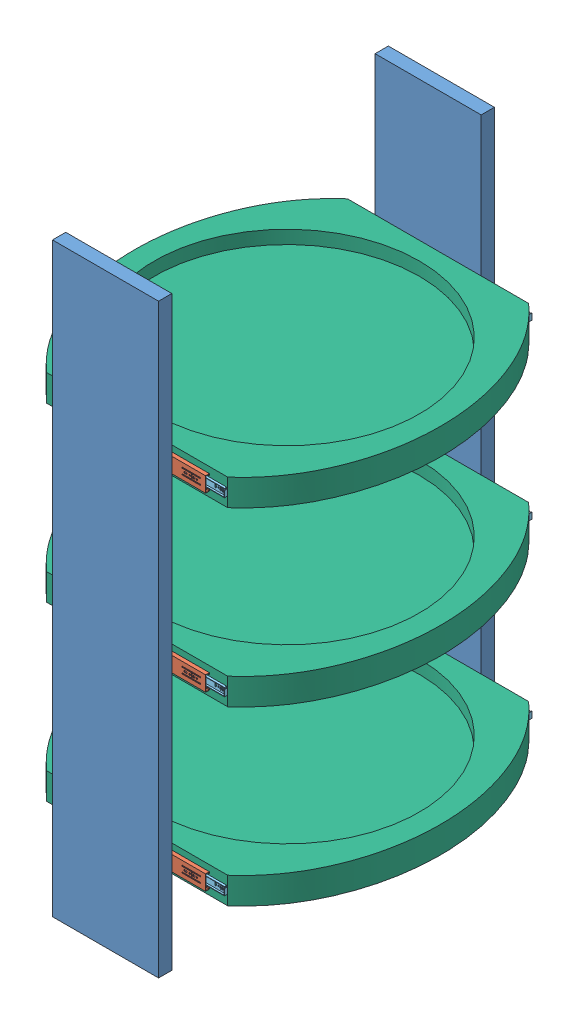
SolidWorks assembly second_prototype, configuration Default. Lengths in mm.
Overall size (230.71 442 253.27).
35 component instances, 6 part files, 39 mates.
Components (placement in the parent):
- slider_holder-1: slider_holder [Default] at (0 0 117.4091) size (80 442 10)
- slider_holder-2: slider_holder [Default] at (0 0 -125.863) size (80 442 10)
- 2831110-21: 2831110 [Default] at (-216.0204 -151 -117.7235) x (0 0 1) z (1 0 0) size (3.17 11.42 125.91) (flexible)
  - 3832-0045TR Outer Member-1: 3832-0045TR Outer Member [Default] at origin size (2.85 11.42 112.5)
  - 3832TR Touch Release-1: 3832TR Touch Release [Default] at (-5.6264 0.6754 178.2964) x (0 -1 0) z (1 0 0) size (10.79 18 2.25)
  - 3832-0045TR Inter-1: 3832-0045TR Inter [Default] at (-0.6578 0.0001 415.8579) x (0 1 0) z (0 0 -1) size (8.7 2.43 90.5)
  - 3832-0045TR Inner Member-1: 3832-0045TR Inner Member [Default] at (-1.9688 0 36.7668) x (0 -1 0) z (0 0 1) size (6.1 2.47 102)
- 2831110-22: 2831110 [Default] at (-216.0204 -151 109.2696) x (0 0 -1) z (1 0 0) size (3.17 11.42 125.91) (flexible)
  - 3832-0045TR Outer Member-1: 3832-0045TR Outer Member [Default] at origin size (2.85 11.42 112.5)
  - 3832TR Touch Release-1: 3832TR Touch Release [Default] at (-5.6264 0.6754 178.2964) x (0 -1 0) z (1 0 0) size (10.79 18 2.25)
  - 3832-0045TR Inter-1: 3832-0045TR Inter [Default] at (-0.6578 0.0001 415.8579) x (0 1 0) z (0 0 -1) size (8.7 2.43 90.5)
  - 3832-0045TR Inner Member-1: 3832-0045TR Inner Member [Default] at (-1.9688 0 36.7668) x (0 -1 0) z (0 0 1) size (6.1 2.47 102)
- dispenserHolder-12: dispenserHolder [Default] at (10.059 -151 -4.2269) x (-1 0 0) z (0 0 -1) size (230.71 20.02 226.94)
- 2831110-27: 2831110 [Default] at (-216.0204 -21 -117.7235) x (0 0 1) z (1 0 0) size (3.17 11.42 125.91) (flexible)
  - 3832-0045TR Outer Member-1: 3832-0045TR Outer Member [Default] at origin size (2.85 11.42 112.5)
  - 3832TR Touch Release-1: 3832TR Touch Release [Default] at (-5.6264 0.6754 178.2964) x (0 -1 0) z (1 0 0) size (10.79 18 2.25)
  - 3832-0045TR Inter-1: 3832-0045TR Inter [Default] at (-0.6578 0.0001 415.8579) x (0 1 0) z (0 0 -1) size (8.7 2.43 90.5)
  - 3832-0045TR Inner Member-1: 3832-0045TR Inner Member [Default] at (-1.9688 0 36.7668) x (0 -1 0) z (0 0 1) size (6.1 2.47 102)
- 2831110-28: 2831110 [Default] at (-216.0204 -21 109.2696) x (0 0 -1) z (1 0 0) size (3.17 11.42 125.91) (flexible)
  - 3832-0045TR Outer Member-1: 3832-0045TR Outer Member [Default] at origin size (2.85 11.42 112.5)
  - 3832TR Touch Release-1: 3832TR Touch Release [Default] at (-5.6264 0.6754 178.2964) x (0 -1 0) z (1 0 0) size (10.79 18 2.25)
  - 3832-0045TR Inter-1: 3832-0045TR Inter [Default] at (-0.6578 0.0001 415.8579) x (0 1 0) z (0 0 -1) size (8.7 2.43 90.5)
  - 3832-0045TR Inner Member-1: 3832-0045TR Inner Member [Default] at (-1.9688 0 36.7668) x (0 -1 0) z (0 0 1) size (6.1 2.47 102)
- dispenserHolder-15: dispenserHolder [Default] at (10.059 -21 -4.2269) x (-1 0 0) z (0 0 -1) size (230.71 20.02 226.94)
- 2831110-29: 2831110 [Default] at (-216.0204 109 -117.7235) x (0 0 1) z (1 0 0) size (3.17 11.42 125.91) (flexible)
  - 3832-0045TR Outer Member-1: 3832-0045TR Outer Member [Default] at origin size (2.85 11.42 112.5)
  - 3832TR Touch Release-1: 3832TR Touch Release [Default] at (-5.6264 0.6754 178.2964) x (0 -1 0) z (1 0 0) size (10.79 18 2.25)
  - 3832-0045TR Inter-1: 3832-0045TR Inter [Default] at (-0.6578 0.0001 415.8579) x (0 1 0) z (0 0 -1) size (8.7 2.43 90.5)
  - 3832-0045TR Inner Member-1: 3832-0045TR Inner Member [Default] at (-1.9688 0 36.7668) x (0 -1 0) z (0 0 1) size (6.1 2.47 102)
- 2831110-30: 2831110 [Default] at (-216.0204 109 109.2696) x (0 0 -1) z (1 0 0) size (3.17 11.42 125.91) (flexible)
  - 3832-0045TR Outer Member-1: 3832-0045TR Outer Member [Default] at origin size (2.85 11.42 112.5)
  - 3832TR Touch Release-1: 3832TR Touch Release [Default] at (-5.6264 0.6754 178.2964) x (0 -1 0) z (1 0 0) size (10.79 18 2.25)
  - 3832-0045TR Inter-1: 3832-0045TR Inter [Default] at (-0.6578 0.0001 415.8579) x (0 1 0) z (0 0 -1) size (8.7 2.43 90.5)
  - 3832-0045TR Inner Member-1: 3832-0045TR Inner Member [Default] at (-1.9688 0 36.7668) x (0 -1 0) z (0 0 1) size (6.1 2.47 102)
- dispenserHolder-16: dispenserHolder [Default] at (10.059 109 -4.2269) x (-1 0 0) z (0 0 -1) size (230.71 20.02 226.94)
Mates (geometry in assembly coordinates):
- Coincident31: coincident aligned: plane of slider_holder-1 through (40 221 122.4091) normal (1 0 0); plane of slider_holder-2 through (40 221 -120.863) normal (1 0 0)
- Coincident32: coincident aligned: plane of slider_holder-1 through (-40 221 122.4091) normal (0 1 0); plane of slider_holder-2 through (-40 221 -120.863) normal (0 1 0)
- Coincident33: coincident anti-aligned: plane of 2831110-21/3832-0045TR Inner Member-1 through (-23.1493 -151 -117.688) normal (0 0 1); plane of dispenserHolder-12 through (125.9996 -161.01 -117.688) normal (0 0 -1)
- Coincident34: coincident anti-aligned: plane of slider_holder-2 through (0 0 -120.863) normal (0 0 1); plane of 2831110-21/3832-0045TR Outer Member-1 through (-47.0625 -151 -120.863) normal (0 0 -1)
- Coincident35: coincident anti-aligned: plane of slider_holder-1 through (0 0 112.4091) normal (0 0 -1); plane of 2831110-22/3832-0045TR Outer Member-1 through (-47.0625 -151 112.4091) normal (0 0 1)
- Coincident36: coincident anti-aligned: plane of 2831110-22/3832-0045TR Inner Member-1 through (-23.1493 -151 109.2341) normal (0 0 -1); plane of dispenserHolder-12 through (125.9996 -161.01 109.2341) normal (0 0 1)
- Coincident37: coincident aligned: plane of 2831110-21/3832-0045TR Inner Member-1 through (78.8507 -147.95 -117.688) normal (1 0 0); plane of 2831110-22/3832-0045TR Inner Member-1 through (78.8507 -154.05 109.2341) normal (1 0 0)
- Width7: width anti-aligned: plane of 2831110-22/3832-0045TR Outer Member-1 through (-47.0625 -145.2875 112.4091) normal (0 1 0); plane of dispenserHolder-12 through (65.4375 -156.7125 112.4091) normal (0 -1 0); plane of 2831110-22/3832-0045TR Outer Member-1 through (10.059 -161 -4.2269) normal (0 -1 0); plane of dispenserHolder-12 through (10.059 -141 -4.2269) normal (0 1 0)
- Width8: width aligned: plane of 2831110-21/3832-0045TR Outer Member-1 through (65.4375 -145.2875 -120.863) normal (0 1 0); plane of dispenserHolder-12 through (-47.0625 -156.7125 -120.863) normal (0 -1 0); plane of 2831110-21/3832-0045TR Outer Member-1 through (10.059 -141 -4.2269) normal (0 1 0); plane of dispenserHolder-12 through (10.059 -161 -4.2269) normal (0 -1 0)
- Coincident39: coincident anti-aligned: plane of 2831110-27/3832-0045TR Inner Member-1 through (-23.1493 -21 -117.688) normal (0 0 1); plane of dispenserHolder-15 through (125.9996 -31.01 -117.688) normal (0 0 -1)
- Width9: width aligned: plane of 2831110-27/3832-0045TR Outer Member-1 through (65.4375 -15.2875 -120.863) normal (0 1 0); plane of dispenserHolder-15 through (-47.0625 -26.7125 -120.863) normal (0 -1 0); plane of 2831110-27/3832-0045TR Outer Member-1 through (10.059 -11 -4.2269) normal (0 1 0); plane of dispenserHolder-15 through (10.059 -31 -4.2269) normal (0 -1 0)
- Width10: width anti-aligned: plane of 2831110-28/3832-0045TR Outer Member-1 through (-47.0625 -15.2875 112.4091) normal (0 1 0); plane of dispenserHolder-15 through (65.4375 -26.7125 112.4091) normal (0 -1 0); plane of 2831110-28/3832-0045TR Outer Member-1 through (10.059 -31 -4.2269) normal (0 -1 0); plane of dispenserHolder-15 through (10.059 -11 -4.2269) normal (0 1 0)
- Coincident40: coincident aligned: plane of 2831110-27/3832-0045TR Inner Member-1 through (78.8507 -17.95 -117.688) normal (1 0 0); plane of 2831110-28/3832-0045TR Inner Member-1 through (78.8507 -24.05 109.2341) normal (1 0 0)
- Coincident41: coincident anti-aligned: plane of 2831110-28/3832-0045TR Inner Member-1 through (-23.1493 -21 109.2341) normal (0 0 -1); plane of dispenserHolder-15 through (125.9996 -31.01 109.2341) normal (0 0 1)
- Coincident42: coincident anti-aligned: plane of slider_holder-1 through (0 0 112.4091) normal (0 0 -1); plane of 2831110-28/3832-0045TR Outer Member-1 through (-47.0625 -21 112.4091) normal (0 0 1)
- Coincident43: coincident anti-aligned: plane of 2831110-29/3832-0045TR Inner Member-1 through (-23.1493 109 -117.688) normal (0 0 1); plane of dispenserHolder-16 through (125.9996 98.99 -117.688) normal (0 0 -1)
- Width11: width aligned: plane of 2831110-29/3832-0045TR Outer Member-1 through (65.4375 114.7125 -120.863) normal (0 1 0); plane of dispenserHolder-16 through (-47.0625 103.2875 -120.863) normal (0 -1 0); plane of 2831110-29/3832-0045TR Outer Member-1 through (10.059 119 -4.2269) normal (0 1 0); plane of dispenserHolder-16 through (10.059 99 -4.2269) normal (0 -1 0)
- Width12: width anti-aligned: plane of 2831110-30/3832-0045TR Outer Member-1 through (-47.0625 114.7125 112.4091) normal (0 1 0); plane of dispenserHolder-16 through (65.4375 103.2875 112.4091) normal (0 -1 0); plane of 2831110-30/3832-0045TR Outer Member-1 through (10.059 99 -4.2269) normal (0 -1 0); plane of dispenserHolder-16 through (10.059 119 -4.2269) normal (0 1 0)
- Coincident44: coincident aligned: plane of 2831110-29/3832-0045TR Inner Member-1 through (78.8507 112.05 -117.688) normal (1 0 0); plane of 2831110-30/3832-0045TR Inner Member-1 through (78.8507 105.95 109.2341) normal (1 0 0)
- Coincident45: coincident anti-aligned: plane of 2831110-30/3832-0045TR Inner Member-1 through (-23.1493 109 109.2341) normal (0 0 -1); plane of dispenserHolder-16 through (125.9996 98.99 109.2341) normal (0 0 1)
- Coincident46: coincident anti-aligned: plane of slider_holder-1 through (0 0 112.4091) normal (0 0 -1); plane of 2831110-30/3832-0045TR Outer Member-1 through (-47.0625 109 112.4091) normal (0 0 1)
- Distance3: distance = 110 mm anti-aligned: plane of dispenserHolder-16 through (10.059 99 -4.2269) normal (0 -1 0); plane of dispenserHolder-15 through (10.059 -11 -4.2269) normal (0 1 0)
- Distance4: distance = 110 mm anti-aligned: plane of dispenserHolder-15 through (10.059 -31 -4.2269) normal (0 -1 0); plane of dispenserHolder-12 through (10.059 -141 -4.2269) normal (0 1 0)
- Distance10: distance = 60 mm aligned: plane of dispenserHolder-12 through (10.059 -161 -4.2269) normal (0 -1 0); plane of slider_holder-2 through (-40 -221 -120.863) normal (0 -1 0)
- Concentric2: concentric aligned: cylinder of dispenserHolder-15 through (9.9598 -7.3618 -4.2269) axis (0 -1 0) radius 100; cylinder of dispenserHolder-16 through (9.9598 122.6382 -4.2269) axis (0 -1 0) radius 100
- Concentric3: concentric aligned: cylinder of dispenserHolder-12 through (9.9598 -141 -4.2269) axis (0 -1 0) radius 100; cylinder of dispenserHolder-15 through (9.9598 -11 -4.2269) axis (0 -1 0) radius 100
- Parallel1: parallel aligned: plane of slider_holder-2 through (-40 221 -120.863) normal (0 1 0); plane of dispenserHolder-16 through (10.059 119 -4.2269) normal (0 1 0)
- Distance7: distance = 18 mm: line of dispenserHolder-16 through (50.1817 119 -117.688) axis (0 -1 0); line of slider_holder-2 through (-40 221 -120.863) axis (0 -1 0)
- Distance8: distance = 18 mm: line of slider_holder-2 through (-40 221 -120.863) axis (0 -1 0); line of dispenserHolder-15 through (54.353 -11 -117.688) axis (0 -1 0)
- Distance9: distance = 18 mm: line of slider_holder-2 through (-40 221 -120.863) axis (0 -1 0); line of dispenserHolder-12 through (23.6096 -141 -117.688) axis (0 -1 0)
- Coincident50: coincident anti-aligned: line of 2831110-21/3832-0045TR Inner Member-1 through (78.8507 -148.65 -117.688) axis (0 -1 0); line of dispenserHolder-12 through (78.8507 -161 -117.688) axis (0 1 0)
- Coincident51: coincident: plane of 2831110-27/3832-0045TR Inner Member-1 through (78.8507 -17.95 -117.688) normal (1 0 0); line of dispenserHolder-15 through (78.8507 -31 -117.688) axis (0 1 0)
- Coincident52: coincident: plane of 2831110-29/3832-0045TR Inner Member-1 through (78.8507 112.05 -117.688) normal (1 0 0); line of dispenserHolder-16 through (78.8507 99 -117.688) axis (0 1 0)
- Distance11: distance = 4.5 mm aligned: plane of 2831110-27/3832-0045TR Outer Member-1 through (-44.5 -18.05 -118.013) normal (-1 0 0); plane of slider_holder-2 through (-40 221 -120.863) normal (-1 0 0)
- Distance12: distance = 4.5 mm aligned: plane of slider_holder-2 through (-40 221 -120.863) normal (-1 0 0); plane of 2831110-29/3832-0045TR Outer Member-1 through (-44.5 111.95 -118.013) normal (-1 0 0)
- Distance13: distance = 4.5 mm aligned: plane of 2831110-21/3832-0045TR Outer Member-1 through (-44.5 -148.05 -118.013) normal (-1 0 0); plane of slider_holder-2 through (-40 221 -120.863) normal (-1 0 0)
- Coincident53: coincident aligned: plane of 2831110-21/3832-0045TR Outer Member-1 through (-47.0625 -145.2875 -120.863) normal (-1 0 0); plane of 2831110-22/3832-0045TR Outer Member-1 through (-47.0625 -156.7125 112.4091) normal (-1 0 0)
- Coincident54: coincident aligned: plane of 2831110-27/3832-0045TR Outer Member-1 through (-47.0625 -15.2875 -120.863) normal (-1 0 0); plane of 2831110-28/3832-0045TR Outer Member-1 through (-47.0625 -26.7125 112.4091) normal (-1 0 0)
- Coincident55: coincident aligned: plane of 2831110-29/3832-0045TR Outer Member-1 through (-47.0625 114.7125 -120.863) normal (-1 0 0); plane of 2831110-30/3832-0045TR Outer Member-1 through (-47.0625 103.2875 112.4091) normal (-1 0 0)
